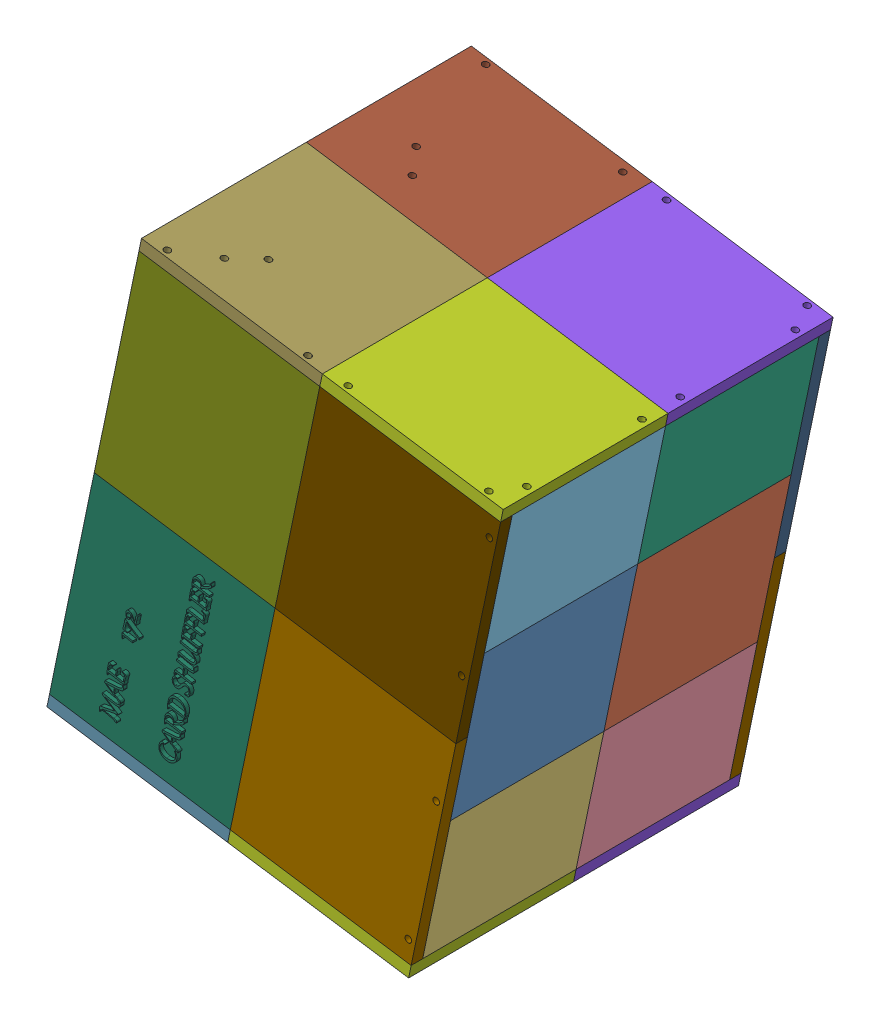
SolidWorks assembly base &elevator, configuration Default. Lengths in mm.
Overall size (222.75 257.54 186.58).
67 component instances, 35 part files, 12 mates.
Components (placement in the parent):
- plate assembly-1: plate assembly [Default] at (101.6343 -292.0056 -176.5006) x (0.177988 0.983429 -0.034475) z (0.983457 -0.178972 -0.027936) size (224 174 180)
  - 7mm base plate-1: 7mm base plate [Default] at (51.5437 66.474 59.5493) size (98 89 7)
  - 7mm base plate 2-1: 7mm base plate 2 [Default] at (51.5437 -13.526 66.5493) x (1 0 0) z (0 0 -1) size (80 80 7)
  - 7mm base plate 3-1: 7mm base plate 3 [Default] at (-21.4563 66.474 66.5493) x (1 0 0) z (0 0 -1) size (66 90 7)
  - 7mm base plate 4-1: 7mm base plate 4 [Default] at (-21.4563 -13.526 66.5493) x (1 0 0) z (0 0 -1) size (76 80 7)
  - 7mm base plate 5-1: 7mm base plate 5 [Default] at (124.5437 66.474 66.5493) x (1 0 0) z (0 0 -1) size (66 90 7)
  - 7mm base plate 6-1: 7mm base plate 6 [Default] at (124.5437 -13.526 66.5493) x (1 0 0) z (0 0 -1) size (76 80 7)
  - 6mm side plate1-1: 6mm side plate1 [Default] at (-60.4563 69.474 21.5493) x (0 -1 0) z (1 0 0) size (86 100 6)
  - 6mm side plate2-1: 6mm side plate2 [Default] at (-54.4563 -16.526 21.5493) x (0 1 0) z (-1 0 0) size (96 90 6)
  - 6mm back plate1-1: 6mm back plate1 [Default] at (-1.4563 -53.526 21.5493) x (-1 0 0) z (0 -1 0) size (106 100 6)
  - 6mm back plate1-2: 6mm back plate1 [Default] at (-1.4563 112.474 21.5493) x (-1 0 0) z (0 -1 0) size (106 100 6)
  - 6mm back plate2( back)-2: 6mm back plate2( back) [Default] at (104.5437 -59.526 21.5493) x (1 0 0) z (0 1 0) size (116 90 21)
  - 6mm side plate2-3: 6mm side plate2 [Default] at (163.5437 -16.526 21.5493) x (0 1 0) z (-1 0 0) size (96 90 6)
  - 6mm side plate1-3: 6mm side plate1 [Default] at (157.5437 69.474 21.5493) x (0 -1 0) z (1 0 0) size (86 100 6)
  - 6mm side plate3(right)-2: 6mm side plate3(right) [Default] at (163.5437 -16.526 -68.4507) x (0 1 0) z (-1 0 0) size (86 100 6)
  - 6mm side plate4(right)-2: 6mm side plate4(right) [Default] at (163.5437 69.474 -68.4507) x (0 1 0) z (-1 0 0) size (96 90 6)
  - 6mm side plate3-3: 6mm side plate3 [Default] at (-54.4563 -16.3793 -68.4507) x (0 1 0) z (-1 0 0) size (86 100 6)
  - 6mm side plate4-3: 6mm side plate4 [Default] at (-54.4563 69.474 -68.4507) x (0 1 0) z (-1 0 0) size (96 90 6)
  - 6mm back plate3( front)-1: 6mm back plate3( front) [Default] at (-1.4563 106.474 -68.4507) x (1 0 0) z (0 1 0) size (116 90 8)
  - 6mm back plate4-1: 6mm back plate4 [Default] at (104.5437 106.474 -68.4507) x (1 0 0) z (0 1 0) size (106 100 6)
  - 6mm back plate3( back)-1: 6mm back plate3( back) [Default] at (-1.4563 -59.3793 -68.4507) x (1 0 0) z (0 1 0) size (116 90 6)
  - 6mm back plate4-2: 6mm back plate4 [Default] at (104.5437 -59.3793 -68.4507) x (1 0 0) z (0 1 0) size (106 100 6)
  - 6mm back plate2-3: 6mm back plate2 [Default] at (104.5437 106.474 21.5493) x (1 0 0) z (0 1 0) size (116 90 6)
- 1-1: 1 [Default] at (104.3078 6.4769 68.7799) x (0.983457 -0.178972 -0.027936) z (0.033643 0.028932 0.999015) size (152.39 137.84 144.65)
  - rack platform V3-1: rack platform V3 [Default] at (74.2988 -233.9108 -214.7311) x (0 1 0) z (1 0 0) size (21 21 94)
  - rack base V5-1: rack base V5 [Default] at (75.6923 -247.0108 -212.3311) x (0 0 -1) z (0 1 0) size (60 80.6 64)
  - spur gear_am-1: spur gear_am [Metric - Spur gear 0.9M 16T 20PA 7FW ---S16N75H50L3N] at (51.4423 -230.5108 -195.1382) x (0 -1 0) z (-0.995823 0 -0.09131) size (7 15.96 15.96)
  - rack spur rectangular_am-1: rack spur rectangular_am [Metric - Rack-spur - rectangular 0.9M 20PA 8FW 10PH 80L---SAll] at (35.2988 -237.9108 -212.7311) x (1 0 0) z (0 -1 0) size (80 10.9 8)
  - poker case assembly 2-1: poker case assembly 2 [Default] at (106.031 -207.2338 -272.3389) x (0 -1 0) z (-1 0 0) size (137.84 144.65 92.58)
    - poker case base 1-1: poker case base 1 [Default] at (25.1895 51.145 81.2322) size (67.62 96 14)
    - poker case base 2-1: poker case base 2 [Default] at (26.6771 63.6078 81.2322) size (74.12 104 60)
    - Motor& Roller Assembly-1: Motor& Roller Assembly [Default] at (50.9792 46.5267 41.0782) x (0.457967 -0.029593 -0.888476) z (-0.261122 0.950879 -0.166268) size (38.09 49.96 91.68)
      - M4 Nut-1: M4 Nut [Default] at (-57.6078 23.6231 20.5659) x (-0.029593 -0.308146 0.950879) z (-0.746697 -0.625603 -0.225974) size (3.68 8.08 7)
      - New Motor-1: New Motor [Default] at (-55.0798 47.2645 -54.1441) x (0.888476 0.427744 0.166268) z (-0.029593 -0.308146 0.950879) size (12 10.57 80.84)
      - New Motor case2-1: New Motor case2 [Default] at (-61.0264 35.7877 -27.0245) x (0.457967 -0.849754 -0.261122) z (0.029593 0.308146 -0.950879) size (23 30 30.5)
      - New Motor enclosure-1: New Motor enclosure [Default] at (-56.0797 37.2316 -23.2476) x (0.457967 -0.849754 -0.261122) z (0.029593 0.308146 -0.950879) size (18.9 5.4 12)
      - New Motor roller-1: New Motor roller [Default] at (-57.4381 24.395 18.2973) x (0.972856 0.20955 0.098185) z (-0.029593 -0.308146 0.950879) size (20 20 8)
      - Bearing-1: Bearing [Default] at (-57.0267 27.371 7.1805) x (0.911456 -0.398837 -0.100882) z (0.410332 0.863699 0.292664) size (9 4 9)
    - Motor& Roller Assembly-2: Motor& Roller Assembly [Default] at (104.9792 46.5267 41.0782) x (0.457967 -0.029593 -0.888476) z (-0.261122 0.950879 -0.166268) size (38.09 49.96 91.68)
      - M4 Nut-1: M4 Nut [Default] at (-57.6078 23.6231 20.5659) x (-0.029593 -0.308146 0.950879) z (-0.746697 -0.625603 -0.225974) size (3.68 8.08 7)
      - New Motor-1: New Motor [Default] at (-55.0798 47.2645 -54.1441) x (0.888476 0.427744 0.166268) z (-0.029593 -0.308146 0.950879) size (12 10.57 80.84)
      - New Motor case2-1: New Motor case2 [Default] at (-61.0264 35.7877 -27.0245) x (0.457967 -0.849754 -0.261122) z (0.029593 0.308146 -0.950879) size (23 30 30.5)
      - New Motor enclosure-1: New Motor enclosure [Default] at (-56.0797 37.2316 -23.2476) x (0.457967 -0.849754 -0.261122) z (0.029593 0.308146 -0.950879) size (18.9 5.4 12)
      - New Motor roller-1: New Motor roller [Default] at (-57.4381 24.395 18.2973) x (0.972856 0.20955 0.098185) z (-0.029593 -0.308146 0.950879) size (20 20 8)
      - Bearing-1: Bearing [Default] at (-57.0267 27.371 7.1805) x (0.911456 -0.398837 -0.100882) z (0.410332 0.863699 0.292664) size (9 4 9)
  - motor-1: motor [Default] at (51.4423 -259.0108 -200.1382) x (0 1 0) z (0 0 1) size (34 12 10)
  - motor enclosure-1: motor enclosure [Default] at (51.6923 -242.0108 -194.3382) x (0 0 1) z (0 1 0) size (8 28 14)
- right platform assembly (right)-1: right platform assembly (right) [Default] at (126.5531 -60.6704 -180.5081) x (0.033643 0.028932 0.999015) z (-0.177988 -0.983429 0.034475) size (143.99 70.46 93.68)
  - right platform-1: right platform [Default] at (42.4839 61.1666 74.5313) size (105 46.66 67)
  - Motor& Roller Assembly-1: Motor& Roller Assembly [Default] at (26.5612 16.0126 180.8335) x (-0.029593 -0.888476 0.457967) z (0.950879 -0.166268 -0.261122) size (38.09 49.96 91.68)
    - M4 Nut-1: M4 Nut [Default] at (-57.6078 23.6231 20.5659) x (-0.029593 -0.308146 0.950879) z (-0.746697 -0.625603 -0.225974) size (3.68 8.08 7)
    - New Motor-1: New Motor [Default] at (-55.0798 47.2645 -54.1441) x (0.888476 0.427744 0.166268) z (-0.029593 -0.308146 0.950879) size (12 10.57 80.84)
    - New Motor case2-1: New Motor case2 [Default] at (-61.0264 35.7877 -27.0245) x (0.457967 -0.849754 -0.261122) z (0.029593 0.308146 -0.950879) size (23 30 30.5)
    - New Motor enclosure-1: New Motor enclosure [Default] at (-56.0797 37.2316 -23.2476) x (0.457967 -0.849754 -0.261122) z (0.029593 0.308146 -0.950879) size (18.9 5.4 12)
    - New Motor roller-1: New Motor roller [Default] at (-57.4381 24.395 18.2973) x (0.972856 0.20955 0.098185) z (-0.029593 -0.308146 0.950879) size (20 20 8)
    - Bearing-1: Bearing [Default] at (-57.0267 27.371 7.1805) x (0.911456 -0.398837 -0.100882) z (0.410332 0.863699 0.292664) size (9 4 9)
- side platform assembly (left)-3: side platform assembly (left) [Default] at (55.9782 -390.678 -102.6083) x (-0.033643 -0.028932 -0.999015) z (0.177988 0.983429 -0.034475) size (145.65 70.46 100.15)
  - left platform-1: left platform [Default] at (23.4546 48.6452 53.2546) size (105 46.66 67)
  - Motor& Roller Assembly-1: Motor& Roller Assembly [Default] at (41.0357 3.4912 56.9525) x (0.029593 -0.888476 -0.457967) z (-0.950879 -0.166268 0.261122) size (38.09 49.96 91.68)
    - M4 Nut-1: M4 Nut [Default] at (-57.6078 23.6231 20.5659) x (-0.029593 -0.308146 0.950879) z (-0.746697 -0.625603 -0.225974) size (3.68 8.08 7)
    - New Motor-1: New Motor [Default] at (-55.0798 47.2645 -54.1441) x (0.888476 0.427744 0.166268) z (-0.029593 -0.308146 0.950879) size (12 10.57 80.84)
    - New Motor case2-1: New Motor case2 [Default] at (-61.0264 35.7877 -27.0245) x (0.457967 -0.849754 -0.261122) z (0.029593 0.308146 -0.950879) size (23 30 30.5)
    - New Motor enclosure-1: New Motor enclosure [Default] at (-56.0797 37.2316 -23.2476) x (0.457967 -0.849754 -0.261122) z (0.029593 0.308146 -0.950879) size (18.9 5.4 12)
    - New Motor roller-1: New Motor roller [Default] at (-57.4381 24.395 18.2973) x (0.972856 0.20955 0.098185) z (-0.029593 -0.308146 0.950879) size (20 20 8)
    - Bearing-1: Bearing [Default] at (-57.0267 27.371 7.1805) x (0.911456 -0.398837 -0.100882) z (0.410332 0.863699 0.292664) size (9 4 9)
- IRsemsor-1: IRsemsor [Default] at (72.9265 -227.2291 -184.3519) x (-0.983457 0.178972 0.027936) z (0.033643 0.028932 0.999015) size (9.53 19.05 9.41)
- IRsemsor-2: IRsemsor [Default] at (76.3522 -224.3285 -82.3381) x (0.983457 -0.178972 -0.027936) z (-0.033643 -0.028932 -0.999015) size (9.53 19.05 9.41)
Mates (geometry in assembly coordinates):
- Concentric20: concentric aligned: cylinder of plate assembly-1/7mm base plate-1 through (171.9406 -276.2044 -113.2868) axis (-0.983457 0.178972 0.027936) radius 1.6; cylinder of 1-1/rack base V5-1 through (167.0233 -275.3096 -113.1471) axis (-0.983457 0.178972 0.027936) radius 1.5
- Coincident25: coincident anti-aligned: plane of plate assembly-1/7mm base plate-1 through (171.6091 -250.0505 -113.5326) normal (-0.983457 0.178972 0.027936); plane of 1-1/rack base V5-1 through (168.4531 -263.558 -138.1003) normal (0.983457 -0.178972 -0.027936)
- Concentric27: concentric anti-aligned: cylinder of plate assembly-1/6mm side plate3(right)-2 through (44.1119 -115.5478 -183.7037) axis (-0.177988 -0.983429 0.034475) radius 1.6; cylinder of right platform assembly (right)-1/right platform-1 through (42.154 -126.3655 -183.3245) axis (0.177988 0.983429 -0.034475) radius 1.6
- Coincident30: coincident anti-aligned: plane of plate assembly-1/6mm side plate3(right)-2 through (61.8008 -125.3 -196.5293) normal (-0.177988 -0.983429 0.034475); plane of right platform assembly (right)-1/right platform-1 through (55.4225 -123.6121 -181.3109) normal (0.177988 0.983429 -0.034475)
- Parallel5: parallel aligned: plane of plate assembly-1/6mm side plate3(right)-2 through (104.6097 -134.5978 -240.7441) normal (-0.033643 -0.028932 -0.999015); plane of right platform assembly (right)-1/right platform-1 through (32.0812 -153.5696 -184.6622) normal (-0.033643 -0.028932 -0.999015)
- Concentric28: concentric aligned: cylinder of plate assembly-1/6mm side plate4-3 through (8.6749 -327.042 -76.2867) axis (-0.177988 -0.983429 0.034475) radius 1.6; cylinder of side platform assembly (left)-3/left platform-1 through (9.5648 -322.1249 -76.4591) axis (-0.177988 -0.983429 0.034475) radius 1.5
- Parallel6: parallel aligned: plane of plate assembly-1/6mm side plate4-3 through (71.5951 -344.0089 -61.398) normal (0.033643 0.028932 0.999015); plane of side platform assembly (left)-3/left platform-1 through (9.8043 -293.13 -74.8044) normal (0.033643 0.028932 0.999015)
- Coincident33: coincident anti-aligned: plane of plate assembly-1/6mm side plate4-3 through (26.9608 -331.2987 -103.3054) normal (0.177988 0.983429 -0.034475); plane of side platform assembly (left)-3/left platform-1 through (21.0522 -329.2068 -74.1384) normal (-0.177988 -0.983429 0.034475)
- Parallel7: parallel aligned: plane of 1-1/poker case assembly 2-1/poker case base 2-1 through (35.8663 -261.7586 -78.0325) normal (0.033643 0.028932 0.999015); plane of side platform assembly (left)-3/left platform-1 through (9.8043 -293.13 -74.8044) normal (0.033643 0.028932 0.999015)
- Coincident34: coincident aligned: plane of 1-1/poker case assembly 2-1/poker case base 2-1 through (72.5522 -267.877 -179.1894) normal (0.033643 0.028932 0.999015); plane of IRsemsor-1 through (74.3531 -246.7009 -179.8633) normal (0.033643 0.028932 0.999015)
- Coincident36: coincident anti-aligned: plane of 1-1/poker case assembly 2-1/poker case base 2-1 through (77.8654 -242.9904 -79.9905) normal (-0.983457 0.178972 0.027936); plane of IRsemsor-1 through (74.3531 -246.7009 -179.8633) normal (0.983457 -0.178972 -0.027936)
- Coincident37: coincident anti-aligned: plane of 1-1/poker case assembly 2-1/poker case base 2-1 through (77.8654 -242.9904 -79.9905) normal (-0.983457 0.178972 0.027936); plane of IRsemsor-2 through (77.5117 -244.03 -85.7792) normal (0.983457 -0.178972 -0.027936)
